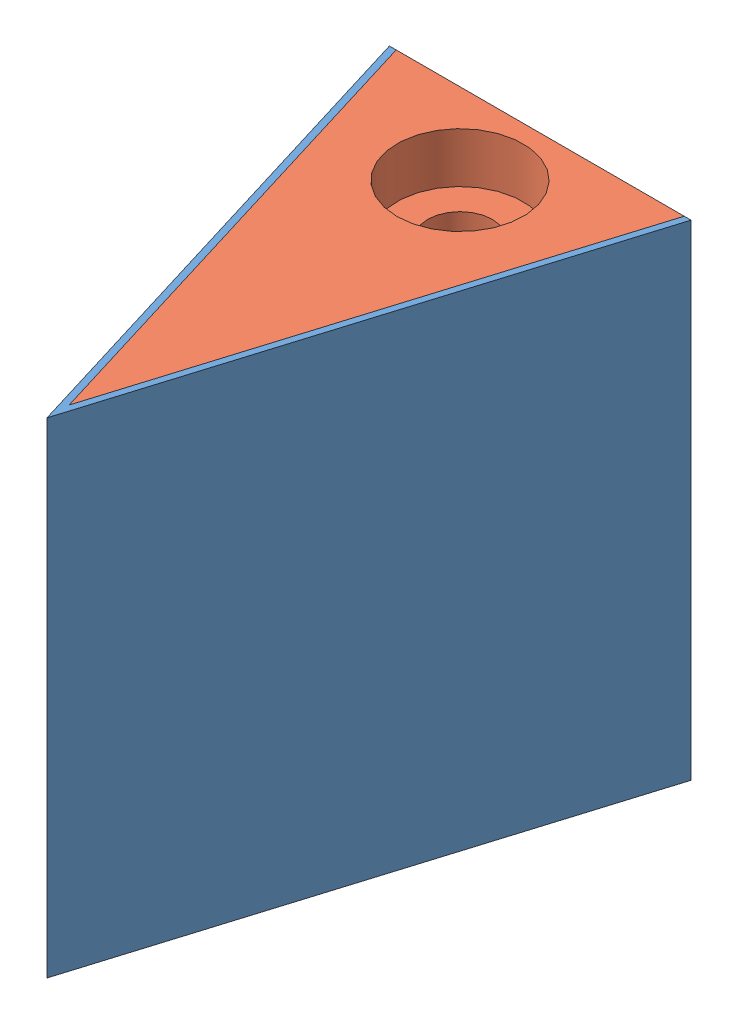
SolidWorks assembly Two Material Solenoid Insert, configuration Default. Lengths in mm.
Overall size (9.32 15 15.25).
2 component instances, 2 part files, 6 mates.
Components (placement in the parent):
- Solenoid Insert Tango Black 2-1: Solenoid Insert Tango Black 2 [Default] at (-6.6316 13.0351 -8.2645) size (9.32 15 15.25)
- Solenoid Insert Verowhite 2-1: Solenoid Insert Verowhite 2 [Default] at (-6.6316 13.0351 -8.2645) size (8.91 15 14.57)
Mates (geometry in assembly coordinates):
- Coincident1: coincident: plane of ? through (4.8936 -0.0028 13.0448) normal (0.956305 0 -0.292372); plane of ? through (4.8936 8.7804 13.0448) normal (-0.956305 0 0.292372)
- Coincident2: coincident: line of ? through (4.8936 0.0072 13.0448) axis (0 1 0); line of ? through (4.8936 0.0072 13.0448) axis (0 1 0)
- Coincident3: coincident aligned: plane of ? through (4.9136 15.0072 -6.0865) normal (0 1 0); plane of ? through (4.9136 15.0072 -6.0865) normal (0 1 0)
- Coincident4: coincident aligned: line of Solenoid Insert Tango Black 2-1 through (-6.6517 10.5351 10.8668) axis (0 1 0); line of Solenoid Insert Verowhite 2-1 through (-6.6517 10.5351 10.8668) axis (0 1 0)
- Coincident5: coincident aligned: plane of Solenoid Insert Tango Black 2-1 through (-6.6316 25.5351 -8.2645) normal (0 1 0); plane of Solenoid Insert Verowhite 2-1 through (-6.6316 25.5351 -8.2645) normal (0 1 0)
- Coincident7: coincident anti-aligned: plane of Solenoid Insert Tango Black 2-1 through (-6.6517 10.5251 10.8668) normal (-0.956305 0 -0.292372); plane of Solenoid Insert Verowhite 2-1 through (-6.6517 10.5251 10.8668) normal (0.956305 0 0.292372)
